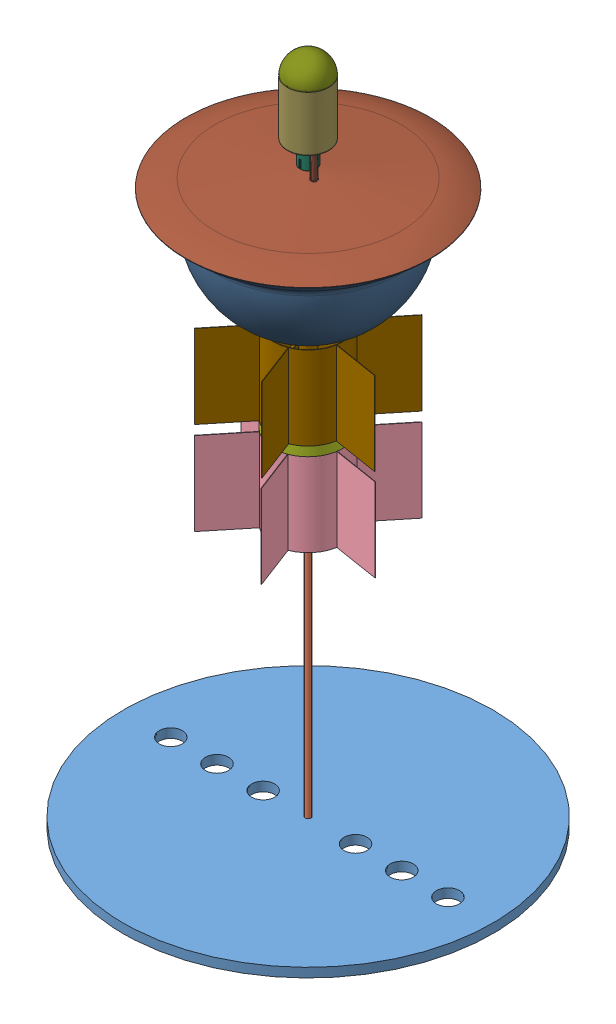
SolidWorks assembly Generator, configuration Default. Lengths in mm.
Overall size (800 1467 800).
20 component instances, 16 part files, 41 mates.
Components (placement in the parent):
- Base-1: Base [Default] at (370.8596 285.4892 658.8292) size (800 20 800)
- Connectingrod-1: Connectingrod [Default] at (370.8596 272.8892 658.8292) size (12 600 12)
- hex nut-fine pitch-style washer-grade ab gb-1: hex nut-fine pitch-style washer-grade ab gb [GB_HEXAGON_TYPE10_1 M12X1.5-S] at (370.8596 284.8892 658.8292) x (1 0 0) z (0 1 0) size (20.78 18 12.6)
- BottomShell-1: BottomShell [Default] at (370.8596 852.8892 658.8292) x (0.63129 0 -0.775547) z (0.775547 0 0.63129) size (350 180 303.61)
- hex nut-fine pitch-style washer-grade ab gb-2: hex nut-fine pitch-style washer-grade ab gb [GB_HEXAGON_TYPE10_1 M12X1.5-S] at (370.8596 840.8892 658.8292) x (1 0 0) z (0 -1 0) size (20.78 18 12.6)
- shaft-1: shaft [Default] at (370.8596 1012.8892 658.8292) x (0.603649 0 0.79725) z (-0.79725 0 0.603649) size (9 533 9)
- spur gear_gb-1: spur gear_gb [GB - Spur gear 2M 10T 20PA 10FW ---S10A75H50L9.0N] at (370.8596 1032.8892 658.8292) x (0 -1 0) z (0 0 1) size (10 22.98 24)
- MiddleRing-1: MiddleRing [Default] at (370.8596 1032.8892 658.8292) x (0.483794 0 -0.875182) z (0.875182 0 0.483794) size (150 20 150)
- internal spur gear_gb-1: internal spur gear_gb [GB - Internal spur gear 2.5M 35T 20PA 10FW ---S35S104OD 1.0AF] at (370.8596 1042.8892 658.8292) x (0 -1 0) z (0.992912 0 0.118852) size (10 104 104)
- TopShell-1: TopShell [Default] at (370.8596 1232.8892 658.8292) x (0.355999 0 0.934487) z (0.934487 0 -0.355999) size (350 180 303.61)
- BottomFloatingPart-1: BottomFloatingPart [Default] at (370.8596 1432.8892 658.8292) x (0.99474 0 0.10243) z (-0.10243 0 0.99474) size (528.85 270 528.85)
- TopFloatingPart-1: TopFloatingPart [Default] at (370.8596 1483.8892 658.8292) x (0.889425 0 0.45708) z (-0.45708 0 0.889425) size (528.85 110 528.85)
- motorbase-1: motorbase [Default] at (370.8596 1574.8892 658.8292) x (-0.889425 0 -0.45708) z (0.45708 0 -0.889425) size (90 120 90)
- motor-1: motor [Default] at (370.8596 1579.8892 658.8292) x (0.45708 0 -0.889425) z (0.889425 0 0.45708) size (50 140 40)
- hex bolts wire hole-reduced shank-b gb-1: hex bolts wire hole-reduced shank-b gb [GB_FASTENER_BOLT_HBWHH M6X25-S] at (377.7158 1570.8892 645.4878) x (0 1 0) z (0 0 1) size (29 10 11.55)
- hex bolts wire hole-reduced shank-b gb-2: hex bolts wire hole-reduced shank-b gb [GB_FASTENER_BOLT_HBWHH M6X25-S] at (364.0034 1570.8892 672.1705) x (0 1 0) z (-0.68676 0 0.726884) size (29 10 11.55)
- hex nut-fine pitch-style washer-grade ab gb-3: hex nut-fine pitch-style washer-grade ab gb [GB_HEXAGON_TYPE10_1 M12X1.5-S] at (397.5423 1580.4892 672.5416) x (1 0 0) z (0 -1 0) size (20.78 18 12.6)
- hex nut-fine pitch-style washer-grade ab gb-4: hex nut-fine pitch-style washer-grade ab gb [GB_HEXAGON_TYPE10_1 M12X1.5-S] at (344.1768 1591.8892 645.1167) x (0.604331 0 0.796734) z (0 1 0) size (20.78 18 12.6)
- Coupling-1: Coupling [Default] at (370.8596 1527.8892 658.8292) x (0.999924 0 -0.012328) z (0.012328 0 0.999924) size (36 40 36)
- LED-1: LED [Default] at (370.8596 1694.8892 658.8292) x (0.992127 0 -0.125234) z (0.125234 0 0.992127) size (90 45 90)
Mates (geometry in assembly coordinates):
- Concentric1: concentric anti-aligned: cylinder of Base-1 through (370.8596 305.4892 658.8292) axis (0 1 0) radius 5.1; cylinder of Connectingrod-1 through (370.8596 872.8892 658.8292) axis (0 -1 0) radius 6
- Concentric2: concentric anti-aligned: cylinder of Connectingrod-1 through (370.8596 872.8892 658.8292) axis (0 -1 0) radius 4.5; circle of hex nut-fine pitch-style washer-grade ab gb-1
- Coincident1: coincident aligned: plane of Connectingrod-1 through (370.8596 272.8892 658.8292) normal (0 -1 0); plane of hex nut-fine pitch-style washer-grade ab gb-1 through (355.2711 272.8892 667.8292) normal (0 -1 0)
- Coincident2: coincident anti-aligned: plane of Base-1 through (370.8596 285.4892 658.8292) normal (0 -1 0); plane of hex nut-fine pitch-style washer-grade ab gb-1 through (370.8596 285.4892 658.8292) normal (0 1 0)
- Concentric3: concentric aligned: cylinder of Connectingrod-1 through (370.8596 872.8892 658.8292) axis (0 -1 0) radius 6; cylinder of BottomShell-1 through (370.8596 872.8892 658.8292) axis (0 -1 0) radius 6
- Coincident3: coincident anti-aligned: plane of Connectingrod-1 through (370.8596 872.8892 658.8292) normal (0 1 0); plane of BottomShell-1 through (370.8596 872.8892 658.8292) normal (0 -1 0)
- Concentric4: concentric anti-aligned: cylinder of Connectingrod-1 through (370.8596 872.8892 658.8292) axis (0 -1 0) radius 6; circle of hex nut-fine pitch-style washer-grade ab gb-2
- Coincident4: coincident anti-aligned: plane of BottomShell-1 through (370.8596 852.8892 658.8292) normal (0 -1 0); plane of hex nut-fine pitch-style washer-grade ab gb-2 through (355.2711 852.8892 649.8292) normal (0 1 0)
- Concentric5: concentric anti-aligned: cylinder of BottomShell-1 through (370.8596 1012.8892 658.8292) axis (0 1 0) radius 5; cylinder of shaft-1 through (370.8596 1545.8892 658.8292) axis (0 -1 0) radius 4.5
- Coincident5: coincident anti-aligned: plane of BottomShell-1 through (370.8596 1012.8892 658.8292) normal (0 1 0); plane of shaft-1 through (370.8596 1012.8892 658.8292) normal (0 -1 0)
- Concentric7: concentric anti-aligned: cylinder of shaft-1 through (370.8596 1545.8892 658.8292) axis (0 -1 0) radius 4.5; cylinder of spur gear_gb-1 through (370.8596 982.8891 658.8292) axis (0 1 0) radius 4.5
- Coincident7: coincident anti-aligned: plane of BottomShell-1 through (370.8596 1022.8892 658.8292) normal (0 1 0); plane of spur gear_gb-1 through (370.8596 1022.8892 658.8292) normal (0 -1 0)
- Concentric8: concentric anti-aligned: cylinder of MiddleRing-1 through (370.8596 1042.8892 658.8292) axis (0 -1 0) radius 52; cylinder of internal spur gear_gb-1 through (370.8596 1052.8892 658.8292) axis (0 1 0) radius 52
- Coincident8: coincident anti-aligned: plane of MiddleRing-1 through (370.8596 1042.8892 658.8292) normal (0 -1 0); plane of internal spur gear_gb-1 through (329.902 1042.8892 653.9265) normal (0 1 0)
- Coincident9: coincident anti-aligned: plane of BottomShell-1 through (370.8596 1032.8892 658.8292) normal (0 1 0); plane of MiddleRing-1 through (370.8596 1032.8892 658.8292) normal (0 -1 0)
- Concentric9: concentric anti-aligned: cylinder of shaft-1 through (370.8596 1545.8892 658.8292) axis (0 -1 0) radius 4.5; circle of MiddleRing-1
- Concentric11: concentric anti-aligned: cylinder of shaft-1 through (370.8596 1545.8892 658.8292) axis (0 -1 0) radius 4.5; cylinder of TopShell-1 through (370.8596 1232.8892 658.8292) axis (0 1 0) radius 5.25
- Coincident11: coincident anti-aligned: plane of MiddleRing-1 through (370.8596 1052.8892 658.8292) normal (0 1 0); plane of TopShell-1 through (370.8596 1052.8892 658.8292) normal (0 -1 0)
- Parallel1: parallel aligned: plane of BottomShell-1 through (261.1612 1032.8892 795.179) normal (0.775547 0 0.63129); plane of TopShell-1 through (260.3839 1052.8892 794.5499) normal (0.775547 0 0.63129)
- Concentric12: concentric aligned: circle of TopShell-1; cylinder of BottomFloatingPart-1 through (370.8596 1213.8892 658.8292) axis (0 1 0) radius 6
- Tangent1: tangent anti-aligned: plane of TopShell-1 through (370.8596 1232.8892 658.8292) normal (0 1 0); sphere of BottomFloatingPart-1
- Concentric13: concentric anti-aligned: cylinder of BottomFloatingPart-1 through (370.8596 1232.8892 658.8292) axis (0 1 0) radius 5; cylinder of TopFloatingPart-1 through (370.8596 1523.8892 658.8292) axis (0 -1 0) radius 5
- Coincident13: coincident anti-aligned: plane of BottomFloatingPart-1 through (370.8596 1483.8892 658.8292) normal (0 1 0); plane of TopFloatingPart-1 through (370.8596 1483.8892 658.8292) normal (0 -1 0)
- Concentric14: concentric anti-aligned: cylinder of motorbase-1 through (370.8596 1594.0313 658.8292) axis (0 -1 0) radius 5; cylinder of motor-1 through (370.8596 1549.8892 658.8292) axis (0 1 0) radius 4.5
- Coincident14: coincident anti-aligned: plane of motorbase-1 through (370.8596 1579.8892 658.8292) normal (0 1 0); plane of motor-1 through (370.8596 1579.8892 658.8292) normal (0 -1 0)
- Concentric15: concentric aligned: cylinder of motorbase-1 through (377.7158 1588.3745 645.4878) axis (0 -1 0) radius 3; cylinder of motor-1 through (377.7158 1604.8892 645.4878) axis (0 -1 0) radius 3
- Concentric16: concentric aligned: cylinder of motor-1 through (377.7158 1604.8892 645.4878) axis (0 -1 0) radius 3; circle of hex bolts wire hole-reduced shank-b gb-1
- Coincident15: coincident anti-aligned: plane of motorbase-1 through (370.8596 1574.8892 658.8292) normal (0 -1 0); plane of hex bolts wire hole-reduced shank-b gb-1 through (377.7158 1574.8892 639.7143) normal (0 1 0)
- Concentric17: concentric aligned: cylinder of motor-1 through (364.0034 1604.8892 672.1705) axis (0 -1 0) radius 3; circle of hex bolts wire hole-reduced shank-b gb-2
- Coincident16: coincident anti-aligned: plane of motorbase-1 through (370.8596 1574.8892 658.8292) normal (0 -1 0); plane of hex bolts wire hole-reduced shank-b gb-2 through (367.9684 1574.8892 667.9739) normal (0 1 0)
- Concentric18: concentric anti-aligned: cylinder of shaft-1 through (370.8596 1545.8892 658.8292) axis (0 -1 0) radius 4.5; circle of motorbase-1
- Concentric22: concentric aligned: cylinder of motor-1 through (370.8596 1549.8892 658.8292) axis (0 1 0) radius 4.5; cylinder of Coupling-1 through (370.8596 1549.8892 658.8292) axis (0 1 0) radius 4.5
- Coincident20: coincident anti-aligned: plane of motor-1 through (370.8596 1549.8892 658.8292) normal (0 -1 0); plane of Coupling-1 through (370.8596 1549.8892 658.8292) normal (0 1 0)
- Concentric23: concentric aligned: cylinder of shaft-1 through (370.8596 1545.8892 658.8292) axis (0 -1 0) radius 4.5; cylinder of Coupling-1 through (370.8596 1545.8892 658.8292) axis (0 -1 0) radius 4.5
- Coincident21: coincident anti-aligned: plane of shaft-1 through (370.8596 1545.8892 658.8292) normal (0 1 0); plane of Coupling-1 through (370.8596 1545.8892 658.8292) normal (0 -1 0)
- Concentric24: concentric anti-aligned: cylinder of TopFloatingPart-1 through (344.1768 1483.8882 645.1167) axis (0 1 0) radius 6; cylinder of motorbase-1 through (344.1768 1597.4254 645.1167) axis (0 -1 0) radius 6.2
- Concentric25: concentric aligned: circle of TopFloatingPart-1; circle of hex nut-fine pitch-style washer-grade ab gb-4
- Concentric26: concentric anti-aligned: circle of TopFloatingPart-1; circle of hex nut-fine pitch-style washer-grade ab gb-3
- Coincident24: coincident anti-aligned: plane of motorbase-1 through (370.8596 1579.8892 658.8292) normal (0 1 0); plane of hex nut-fine pitch-style washer-grade ab gb-4 through (327.5856 1579.8892 638.1359) normal (0 -1 0)
- Coincident25: coincident anti-aligned: plane of motorbase-1 through (370.8596 1579.8892 658.8292) normal (0 1 0); plane of hex nut-fine pitch-style washer-grade ab gb-3 through (397.5423 1579.8892 672.5416) normal (0 -1 0)
- Coincident26: coincident aligned: circle of motorbase-1; circle of LED-1
